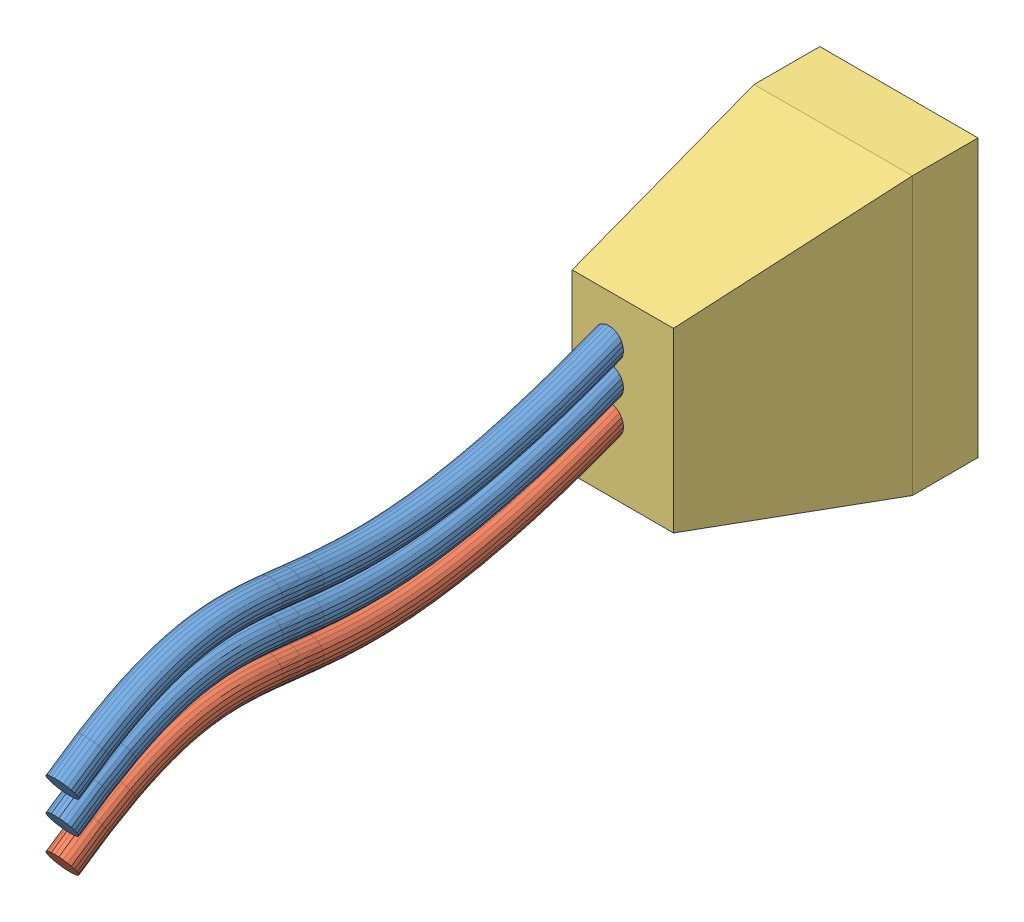
SolidWorks assembly Groupe_4, configuration Standard. Lengths in mm.
Overall size (101.7 178.59 531.1).
5 component instances, 4 part files, 0 mates.
Components (placement in the parent):
- Groupe_8-1: Groupe_8 [Standard] at (-10.9872 -23.8269 84.5461) x (0 1 0) z (-1 0 0) size (130.89 361.96 18.8)
  - Groupe_8-1-1: Groupe_8-1 [Standard] at origin size (109.27 361.96 18.8)
  - Groupe_8-2-1: Groupe_8-2 [Standard] at origin size (88.6 361.96 18.8)
- Groupe_8-2: Groupe_8 [Standard] at (-10.9872 -23.8269 84.5461) x (0 1 0) z (-1 0 0) size (130.89 361.96 18.8)
- Groupe_4-1: Groupe_4 [Standard] at origin size (101.7 177.9 175.36)
